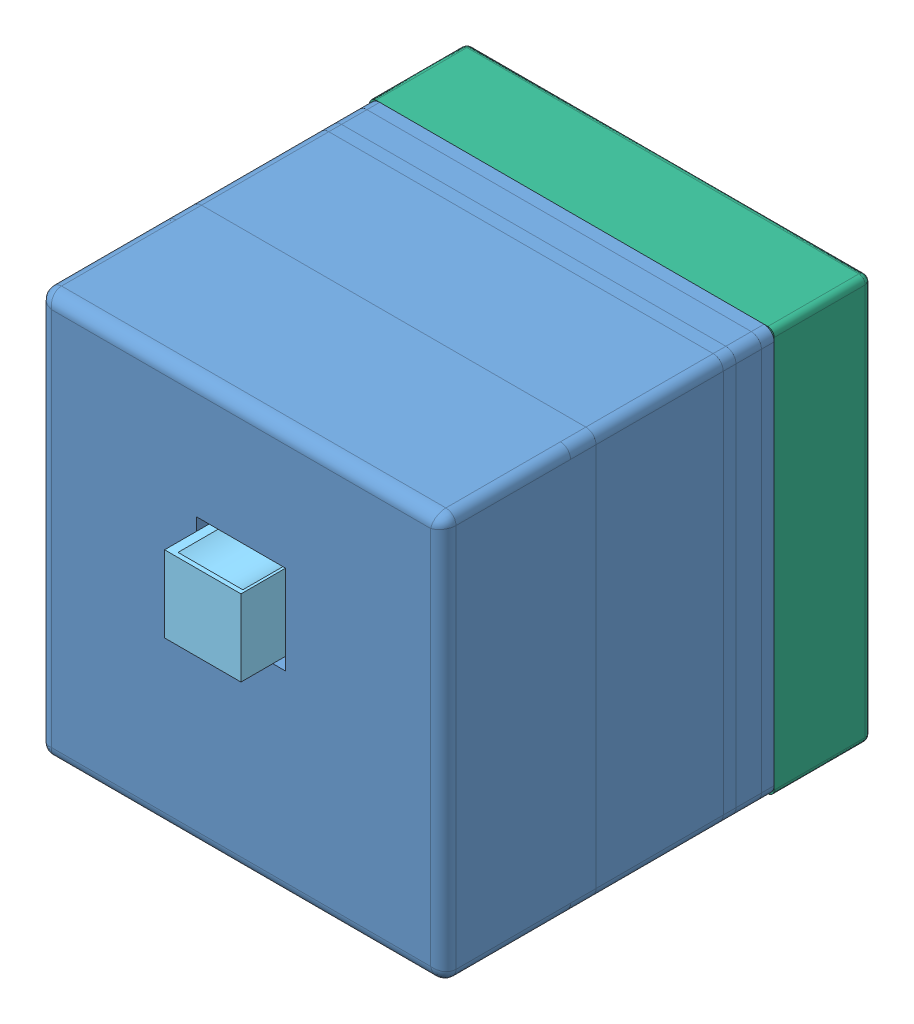
SolidWorks assembly servoShell, configuration Default. Lengths in mm.
Overall size (31.8 32.3 38.65).
30 component instances, 28 part files, 27 mates.
Components (placement in the parent):
- cover_MAIN-1: cover_MAIN [Default] at (-141.0888 46.4042 -3.2479) size (31.8 31.8 29)
- Part1^servoShell-1: Part1^servoShell [Default] at origin (virtual)
- servo-2: servo [Default] at (-7.7138 45.2792 -40.6729) x (0 0 1) z (-1 0 0) size (23.76 12.15 15)
  - servo.stp-1: servo.stp [Default] at origin size (23.76 12.15 15)
    - Block 01.stp-1: Block 01.stp [Default] at (49.925 -22.475 8.625) x (0 0 -1) z (-1 0 0) size (4.01 4.01 15.31)
    - Document.stp-1: Document.stp [Default] at origin size (18 0.5 15)
    - Document-0.stp-1: Document-0.stp [Default] at origin size (2.7 1 1)
    - Document-1.stp-1: Document-1.stp [Default] at origin size (14.95 4.5 4.8)
    - Document-2.stp-1: Document-2.stp [Default] at origin size (0.9 6.9 6.9)
    - Document-3.stp-1: Document-3.stp [Default] at origin size (5 0.51 0.51)
    - Document-4.stp-1: Document-4.stp [Default] at origin size (3 7.75 0.9)
    - Document-5.stp-1: Document-5.stp [Default] at origin size (5 0.51 0.51)
    - Document-6.stp-1: Document-6.stp [Default] at origin size (5 0.51 0.51)
    - Document-7.stp-1: Document-7.stp [Default] at origin size (1.2 2.3 2.3)
    - Document-8.stp-1: Document-8.stp [Default] at origin size (2.2 2.2 2.2)
    - Document-9.stp-1: Document-9.stp [Default] at origin size (5 1.4 4)
    - Document-10.stp-1: Document-10.stp [Default] at origin size (0.6 1 1)
    - Document-11.stp-1: Document-11.stp [Default] at origin size (0.6 1 1)
    - Document-12.stp-1: Document-12.stp [Default] at origin size (0.6 1 1)
    - Document-13.stp-1: Document-13.stp [Default] at origin size (0.6 1 1)
    - Document-14.stp-1: Document-14.stp [Default] at origin size (0.6 1 1)
    - Document-15.stp-1: Document-15.stp [Default] at origin size (0.6 1 1)
    - Document-16.stp-1: Document-16.stp [Default] at origin size (0.6 1 1)
    - Document-17.stp-1: Document-17.stp [Default] at origin size (0.6 1 1)
- Part2^servoShell-1: Part2^servoShell [Default] at (-0.1819 25.3042 1.3124) x (-1 0 0) z (0 -1 0) size (25.28 19.6 2.5)
- Part3^servoShell-1: Part3^servoShell [Default] at (-141.0888 46.4042 21.7521) size (6 6.75 15.8)
- toioBase^servoShell-1: toioBase^servoShell [Default] at (-141.0888 46.4042 -4.2479) x (-1 0 0) z (0 0 -1) size (31.8 31.8 9.65) (virtual)
- Part4^servoShell-1: Part4^servoShell [Default] at (-141.0888 -5.4958 -3.2479) x (-1 0 0) z (0 -1 0) size (5.75 3.25 1.5) (virtual)
- Magnet Mount_3disc^servoShell-1: Magnet Mount_3disc^servoShell [Default] at (-141.0888 46.4042 -11.8979) x (-1 0 0) z (0 0 -1) size (14.6 7.75 1.41) (hidden, virtual)
- MagnetMount_2disc^servoShell-2: MagnetMount_2disc^servoShell [Default] at (-26.4888 46.4042 -4.2479) x (0 0 -1) z (1 0 0) size (1.62 11.6 23.2) (virtual)
Mates (geometry in assembly coordinates):
- Distance4: distance = 2 mm: plane of cover_MAIN-1 through (-141.0888 46.4042 -1.7479) normal (0 0 -1); plane of servo-2/servo.stp-1/Document.stp-1 through (-8.7389 23.5742 0.2521) normal (0 0 -1)
- Parallel1: parallel: plane of cover_MAIN-1 through (-4.1888 25.3042 -10.2479) normal (0 -1 0); plane of servo-2/servo.stp-1/Document-9.stp-1 through (-13.8188 24.2042 7.2821) normal (0 1 0)
- Distance2: distance = 2.75 mm: plane of servo-2/servo.stp-1/Document-4.stp-1 through (-18.3388 20.6992 8.1321) normal (1 0 0); plane of cover_MAIN-1 through (-15.5888 9.9042 10.3526) normal (-1 0 0)
- Coincident5: coincident: plane of servo-2/servo.stp-1/Document.stp-1 through (-7.2188 22.8042 -1.6679) normal (0 1 0); plane of Part2^servoShell-1 through (-0.1819 22.8042 1.3124) normal (0 -1 0)
- Coincident7: coincident: plane of cover_MAIN-1 through (-4.1888 25.3042 -10.2479) normal (0 -1 0); plane of Part2^servoShell-1 through (-0.1819 25.3042 1.3124) normal (0 1 0)
- Distance3: distance = 0.11 mm: plane of Part2^servoShell-1 through (-26.8788 22.8042 20.2521) normal (-1 0 0); plane of cover_MAIN-1 through (-26.9888 50.1254 20.2521) normal (1 0 0)
- InPlace1: in place: plane of cover_MAIN-1 through (-3.9888 25.5042 20.2521) normal (0 0 1); plane of ? through (0 0 20.2521) normal (0 0 1); moOrthogonalPlaneRef_w of cover_MAIN-1 through (-3.9888 25.5042 20.2521) normal (0 0 1); plane of ? through (0 0 20.2521) normal (0 1 0); plane of cover_MAIN-1 through (-3.9888 25.5042 20.2521) normal (0 0 1); plane of ? through (0 0 20.2521) normal (1 0 0); plane of cover_MAIN-1 through (-3.9888 25.5042 21.7521) normal (0 0 1); unknown of Part3^servoShell-1
- Coincident9: coincident: plane of cover_MAIN-1; plane of Part3^servoShell-1
- Coincident10: coincident: moOrthogonalPlaneRef_w of cover_MAIN-1 through (-141.0888 46.4042 21.7521) normal (0 1 0); plane of Part3^servoShell-1 through (-141.0888 46.4042 21.7521) normal (0 1 0)
- Coincident11: coincident: moOrthogonalPlaneRef_w of cover_MAIN-1 through (-141.0888 46.4042 21.7521) normal (-1 0 0); plane of Part3^servoShell-1 through (-141.0888 46.4042 21.7521) normal (1 0 0)
- Coincident8: coincident: plane of cover_MAIN-1 through (-3.9888 25.5042 20.2521) normal (0 0 -1); plane of Part2^servoShell-1 through (-26.8788 22.8042 20.2521) normal (0 0 1)
- InPlace2: in place: plane of cover_MAIN-1 through (-34.9888 -5.4958 -4.2479) normal (0 0 -1); plane of ? through (0 0 -4.2479) normal (0 0 -1); plane of cover_MAIN-1 through (-34.9888 -5.4958 -4.2479) normal (0 0 -1); plane of ? through (0 0 -4.2479) normal (0 1 0); plane of cover_MAIN-1 through (-34.9888 -5.4958 -4.2479) normal (0 0 -1); plane of ? through (0 0 -4.2479) normal (-1 0 0); plane of cover_MAIN-1 through (-34.9888 -5.4958 -4.2479) normal (0 0 -1); unknown of toioBase^servoShell-1
- Coincident9: coincident: plane of cover_MAIN-1; plane of toioBase^servoShell-1
- Coincident10: coincident: moOrthogonalPlaneRef_w of cover_MAIN-1 through (-141.0888 46.4042 -4.2479) normal (0 1 0); plane of toioBase^servoShell-1 through (-141.0888 46.4042 -4.2479) normal (0 1 0)
- Coincident11: coincident: moOrthogonalPlaneRef_w of cover_MAIN-1 through (-141.0888 46.4042 -4.2479) normal (1 0 0); plane of toioBase^servoShell-1 through (-141.0888 46.4042 -4.2479) normal (-1 0 0)
- InPlace3: in place: plane of cover_MAIN-1 through (-34.9888 -5.4958 -3.2479) normal (0 -1 0); plane of ? through (0 -5.4958 0) normal (0 -1 0); plane of cover_MAIN-1 through (-34.9888 -5.4958 -3.2479) normal (0 -1 0); plane of ? through (0 -5.4958 0) normal (0 0 -1); plane of cover_MAIN-1 through (-34.9888 -5.4958 -3.2479) normal (0 -1 0); plane of ? through (0 -5.4958 0) normal (-1 0 0); plane of cover_MAIN-1 through (-34.9888 -5.4958 -3.2479) normal (0 -1 0); unknown of Part4^servoShell-1
- Coincident9: coincident: plane of cover_MAIN-1; plane of Part4^servoShell-1
- Coincident10: coincident: moOrthogonalPlaneRef_w of cover_MAIN-1 through (-141.0888 -5.4958 -3.2479) normal (0 0 -1); plane of Part4^servoShell-1 through (-141.0888 -5.4958 -3.2479) normal (0 0 -1)
- Coincident11: coincident: moOrthogonalPlaneRef_w of cover_MAIN-1 through (-141.0888 -5.4958 -3.2479) normal (1 0 0); plane of Part4^servoShell-1 through (-141.0888 -5.4958 -3.2479) normal (-1 0 0)
- InPlace4: in place: plane of toioBase^servoShell-1 through (-141.0888 46.4042 -11.8979) normal (0 0 -1); plane of ? through (0 0 -11.8979) normal (0 0 -1); plane of toioBase^servoShell-1 through (-141.0888 46.4042 -11.8979) normal (0 0 -1); plane of ? through (0 0 -11.8979) normal (0 1 0); plane of toioBase^servoShell-1 through (-141.0888 46.4042 -11.8979) normal (0 0 -1); plane of ? through (0 0 -11.8979) normal (-1 0 0); plane of toioBase^servoShell-1 through (-141.0888 46.4042 -11.8979) normal (0 0 -1); unknown of Magnet Mount_3disc^servoShell-1
- Coincident9: coincident: plane of toioBase^servoShell-1; plane of Magnet Mount_3disc^servoShell-1
- Coincident10: coincident: moOrthogonalPlaneRef_w of toioBase^servoShell-1 through (-141.0888 46.4042 -11.8979) normal (0 1 0); plane of Magnet Mount_3disc^servoShell-1 through (-141.0888 46.4042 -11.8979) normal (0 1 0)
- Coincident11: coincident: moOrthogonalPlaneRef_w of toioBase^servoShell-1 through (-141.0888 46.4042 -11.8979) normal (1 0 0); plane of Magnet Mount_3disc^servoShell-1 through (-141.0888 46.4042 -11.8979) normal (-1 0 0)
- InPlace5: in place: plane of toioBase^servoShell-1 through (-26.4888 14.0042 -7.6479) normal (1 0 0); plane of ? through (-26.4888 0 0) normal (1 0 0); plane of toioBase^servoShell-1 through (-26.4888 14.0042 -7.6479) normal (1 0 0); plane of ? through (-26.4888 0 0) normal (0 1 0); plane of toioBase^servoShell-1 through (-26.4888 14.0042 -7.6479) normal (1 0 0); plane of ? through (-26.4888 0 0) normal (0 0 -1); plane of toioBase^servoShell-1 through (-26.4888 14.0042 -7.6479) normal (1 0 0); unknown of MagnetMount_2disc^servoShell-2
- Coincident9: coincident: plane of toioBase^servoShell-1; plane of MagnetMount_2disc^servoShell-2
- Coincident10: coincident: moOrthogonalPlaneRef_w of toioBase^servoShell-1 through (-26.4888 46.4042 -4.2479) normal (0 1 0); plane of MagnetMount_2disc^servoShell-2 through (-26.4888 46.4042 -4.2479) normal (0 1 0)
- Coincident11: coincident: moOrthogonalPlaneRef_w of toioBase^servoShell-1 through (-26.4888 46.4042 -4.2479) normal (0 0 1); plane of MagnetMount_2disc^servoShell-2 through (-26.4888 46.4042 -4.2479) normal (0 0 -1)
